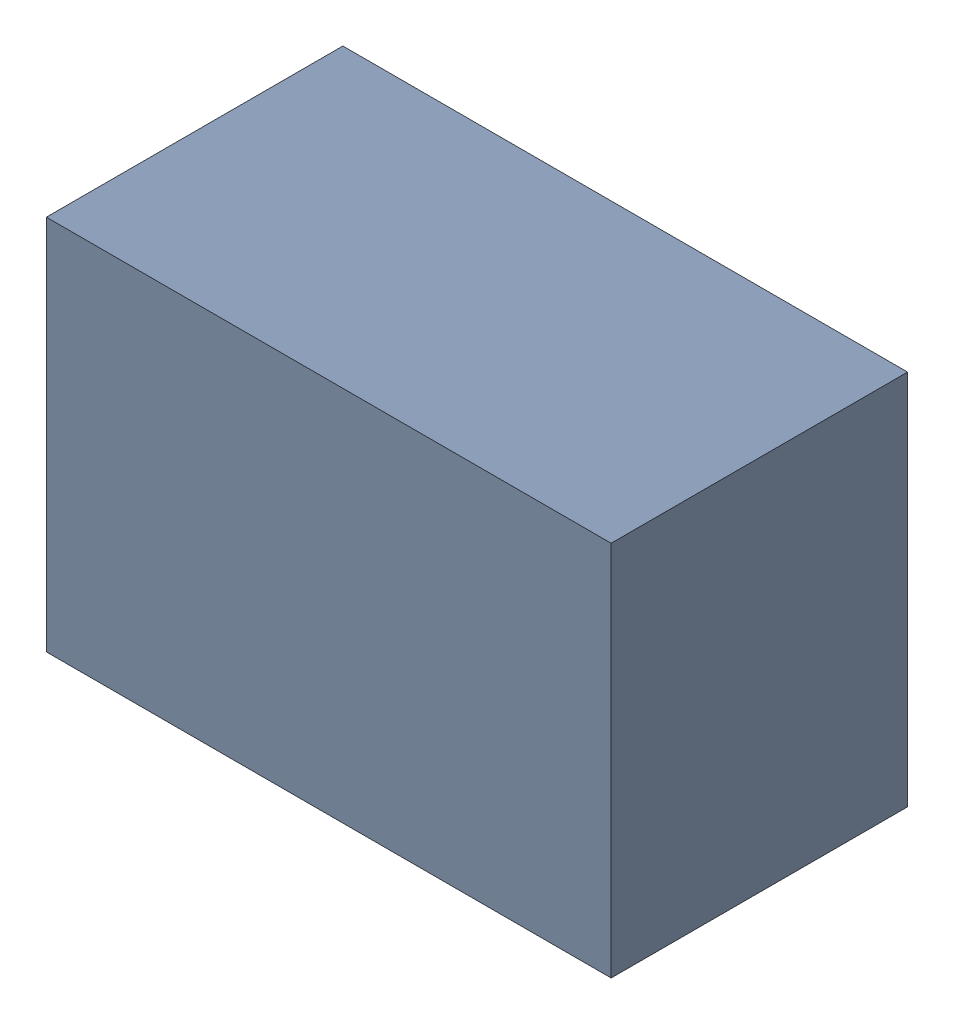
SolidWorks assembly USB23_L2, configuration Default. Lengths in mm.
Overall size (2.29 1.52 1.2).
2 component instances, 1 part files, 0 mates.
Components (placement in the parent):
- 402659088-1: 402659088 [Default] at (156.718 62.738 -2.3024) size (2.29 1.52 1.2)
  - Extruded_28-1: Extruded_28 [Default] at origin size (2.29 1.52 1.2)
